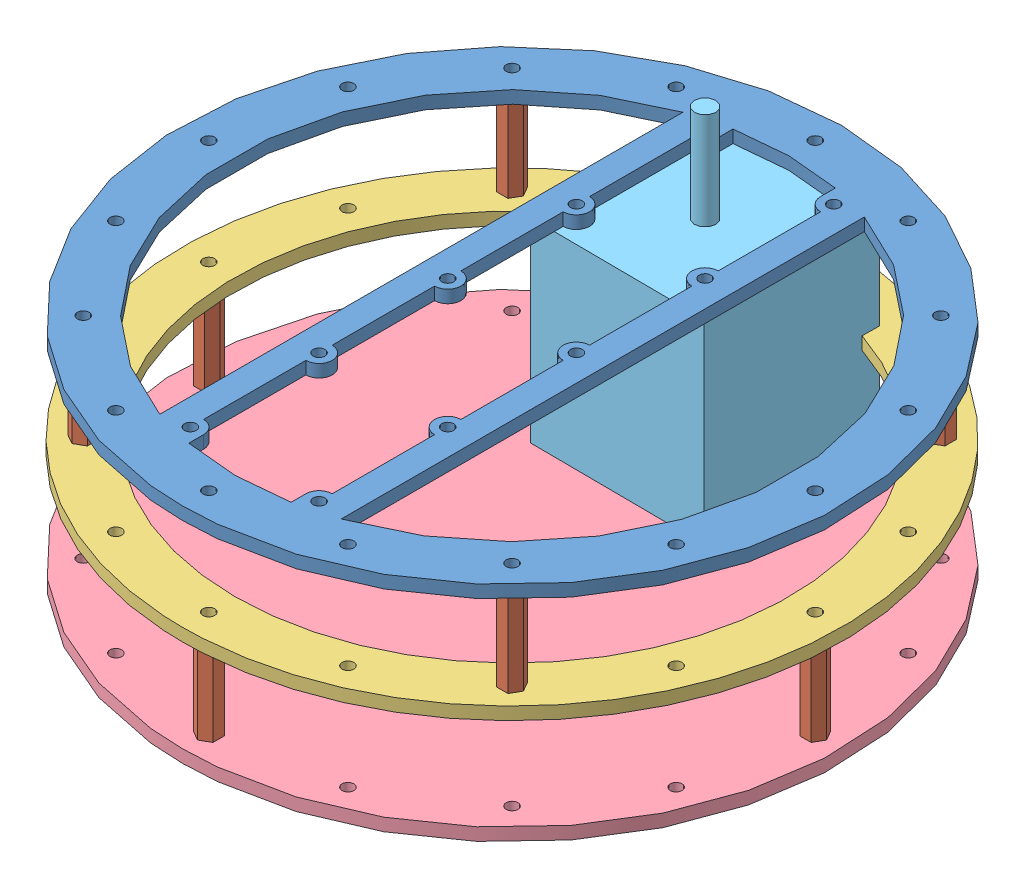
SolidWorks assembly Assem2, configuration Default. Lengths in mm.
Overall size (158.75 74.02 158.75).
13 component instances, 6 part files, 15 mates.
Components (placement in the parent):
- Base Unit-1: Base Unit [Default] at (-15.6008 25.016 -9.7985) size (158.75 3.05 158.75)
- Part11^Assem2-1: Part11^Assem2 [Default] at origin (virtual)
- LHexStandoff-1: LHexStandoff [Default] at (-18.4264 2.7402 134.3541) x (0.866025 0 -0.5) z (0 1 0) size (5.46 4.72 22.28)
- LHexStandoff-2: LHexStandoff [Default] at (128.5518 2.7402 -6.9729) x (-0.5 0 -0.866025) z (0 1 0) size (5.46 4.72 22.28)
- LHexStandoff-3: LHexStandoff [Default] at (-12.7752 2.7402 -153.9512) x (-0.866025 0 0.5) z (0 1 0) size (5.46 4.72 22.28)
- LHexStandoff-4: LHexStandoff [Default] at (-159.7534 2.7402 -12.6242) x (0.5 0 0.866025) z (0 1 0) size (5.46 4.72 22.28)
- Generic Unit-1: Generic Unit [Default] at (-15.6008 -0.3078 -9.7985) size (158.75 3.05 158.75)
- LHexStandoff-5: LHexStandoff [Default] at (33.21 -22.5836 9.6926) x (0.866025 0 -0.5) z (0 1 0) size (5.46 4.72 22.28)
- LHexStandoff-6: LHexStandoff [Default] at (3.8904 -22.5836 -58.6094) x (-0.5 0 -0.866025) z (0 1 0) size (5.46 4.72 22.28)
- LHexStandoff-7: LHexStandoff [Default] at (-64.4116 -22.5836 -29.2897) x (-0.866025 0 0.5) z (0 1 0) size (5.46 4.72 22.28)
- LHexStandoff-8: LHexStandoff [Default] at (-35.092 -22.5836 39.0123) x (0.5 0 0.866025) z (0 1 0) size (5.46 4.72 22.28)
- Bottom Panel-1: Bottom Panel [Default] at (-15.6008 -25.6316 -9.7985) size (158.75 3.05 158.75)
- Stepper mock uo-1: Stepper mock uo [Default] at (-15.6819 1.521 -56.3628) x (0.999976 0 0.006886) z (0 1 0) size (42.01 42.01 70.36)
Mates (geometry in assembly coordinates):
- Concentric1: concentric aligned: circle of Base Unit-1; circle of LHexStandoff-1
- Coincident1: coincident anti-aligned: plane of Base Unit-1 through (-15.6008 25.016 -9.7985) normal (0 -1 0); plane of LHexStandoff-1 through (-18.4264 25.016 134.3541) normal (0 1 0)
- Parallel1: parallel: line of LHexStandoff-1 through (-69.5995 2.7402 40.4741) axis (0 0 1); plane of assembly
- Concentric2: concentric aligned: circle of LHexStandoff-4; circle of Generic Unit-1
- Concentric3: concentric aligned: circle of LHexStandoff-3; circle of Generic Unit-1
- Coincident3: coincident anti-aligned: plane of LHexStandoff-3 through (-12.7752 2.7402 -153.9512) normal (0 -1 0); plane of Generic Unit-1 through (-15.6008 2.7402 -9.7985) normal (0 1 0)
- Concentric4: concentric aligned: circle of Generic Unit-1; circle of LHexStandoff-5
- Coincident4: coincident anti-aligned: plane of Generic Unit-1 through (-15.6008 -0.3078 -9.7985) normal (0 -1 0); plane of LHexStandoff-5 through (33.21 -0.3078 9.6926) normal (0 1 0)
- Parallel2: parallel anti-aligned: plane of Base Unit-1 through (6.2432 25.016 -9.7985) normal (1 0 0); plane of LHexStandoff-5 through (-17.963 -0.3078 -84.1873) normal (-1 0 0)
- Concentric5: concentric aligned: circle of LHexStandoff-7; circle of Bottom Panel-1
- Coincident6: coincident anti-aligned: plane of LHexStandoff-6 through (3.8904 -22.5836 -58.6094) normal (0 -1 0); plane of Bottom Panel-1 through (-15.6008 -22.5836 -9.7985) normal (0 1 0)
- Concentric6: concentric aligned: circle of LHexStandoff-6; circle of Bottom Panel-1
- Concentric7: concentric aligned: cylinder of Base Unit-1 through (-15.6008 28.064 -9.7985) axis (0 -1 0) radius 79.375; cylinder of Generic Unit-1 through (-15.6008 2.7402 -9.7985) axis (0 -1 0) radius 79.375
- Concentric8: concentric aligned: circle of Base Unit-1; circle of Stepper mock uo-1
- Coincident8: coincident anti-aligned: plane of Base Unit-1 through (-15.6008 25.016 -9.7985) normal (0 -1 0); plane of Stepper mock uo-1 through (-15.6819 25.016 -56.3628) normal (0 1 0)
